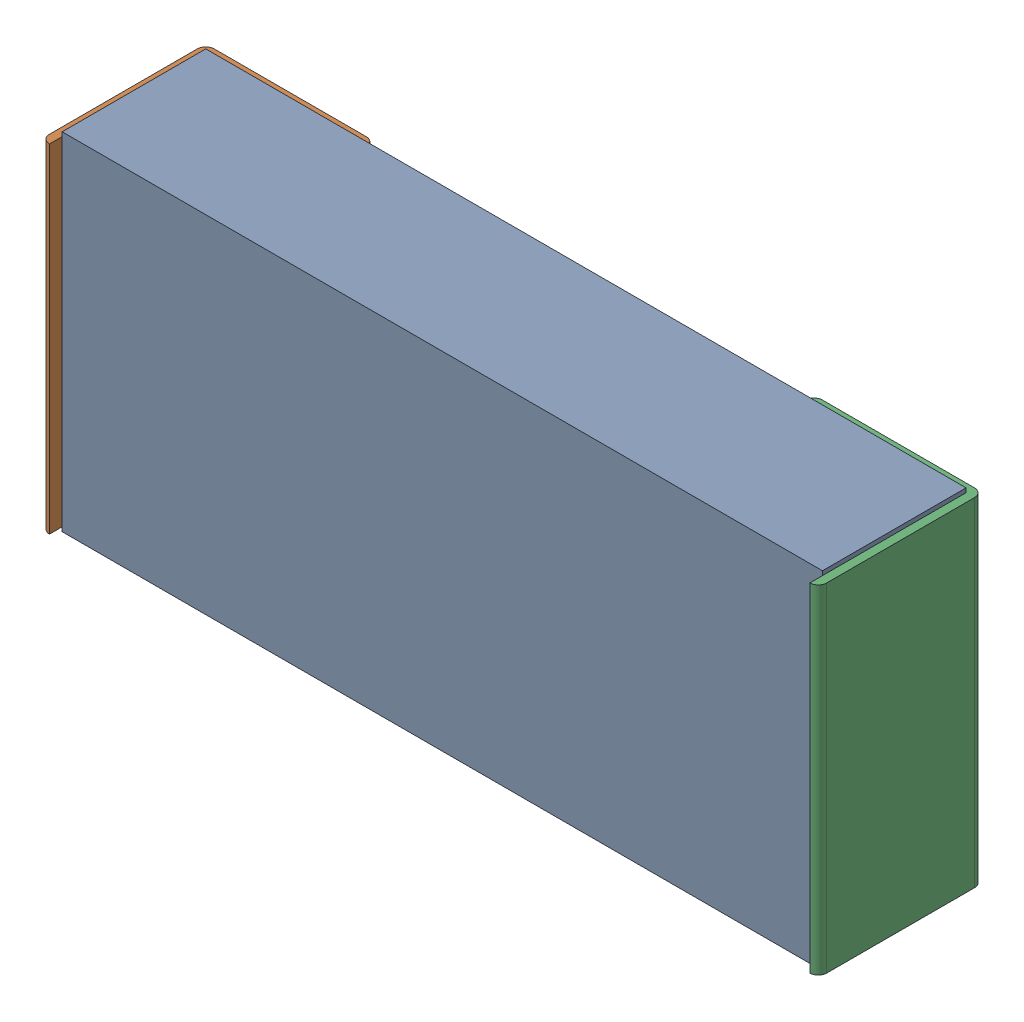
SolidWorks assembly R3, configuration Predeterminado. Lengths in mm.
Overall size (2.34 1.04 0.5).
4 component instances, 3 part files, 0 mates.
Components (placement in the parent):
- Open CASCADE STEP translator 6.8 1.13.1-1: Open CASCADE STEP translator 6.8 1.13.1 [Predeterminado] at origin size (2.34 1.04 0.5)
  - Body_1_5-1: Body_1_5 [Predeterminado] at origin size (2.29 1.04 0.43)
  - Pin_1_4-1: Pin_1_4 [Predeterminado] at (0.3048 0 0) x (-1 0 0) z (0 0 1) size (0.51 1.02 0.5)
  - Pin_2_4-1: Pin_2_4 [Predeterminado] at origin size (0.51 1.02 0.5)
